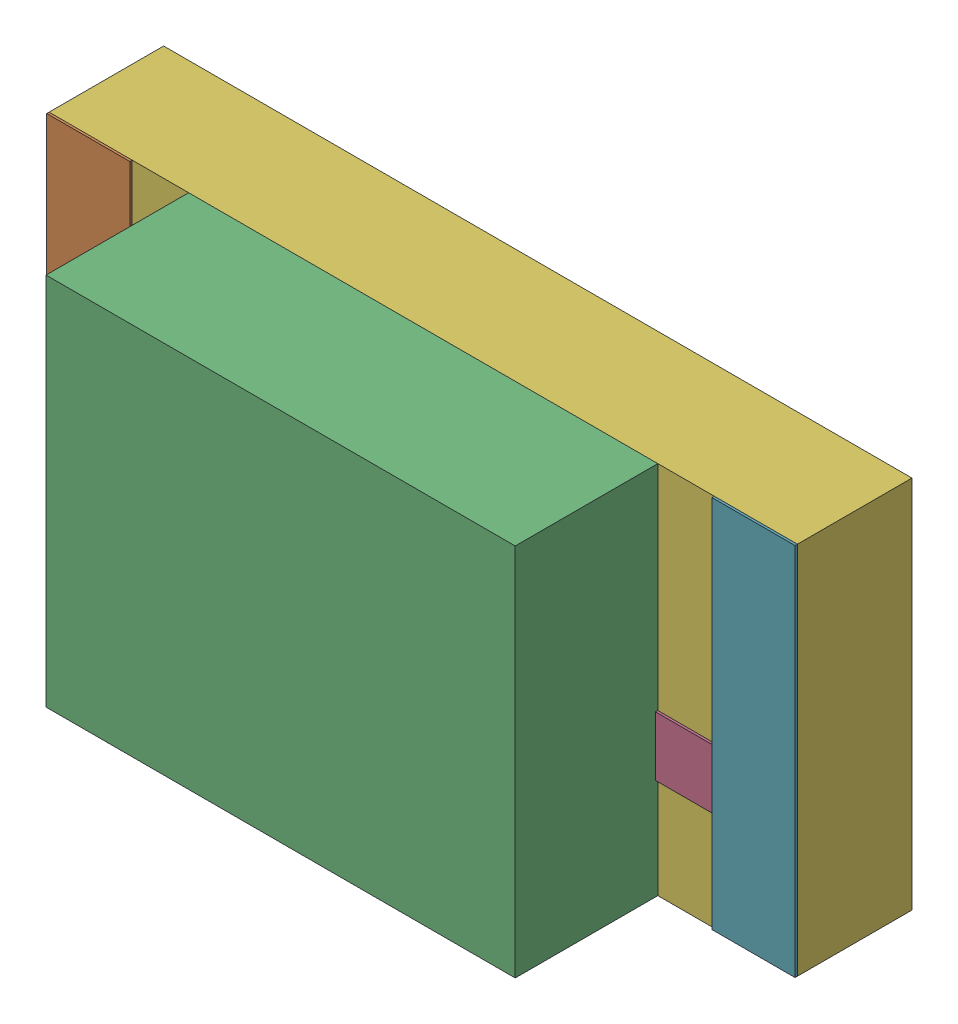
SolidWorks assembly SW3dPS-LED1206Y, configuration Défaut. Lengths in mm.
Overall size (3.2 1.6 1.52).
14 component instances, 6 part files, 0 mates.
Components (placement in the parent):
- SW3dPS-LED1206Y_Board-1: SW3dPS-LED1206Y_Board [Défaut] at (0 0 -0.4039) size (0.03 0.03 0.42)
- SW3dPS-LED1206Y_Open_CASCADE_STEP_translator_6.2_294.2-1: SW3dPS-LED1206Y_Open_CASCADE_STEP_translator_6.2_294.2 [Défaut] at origin size (3.2 1.6 1.1)
  - SW3dPS-LED1206Y_352697808-1: SW3dPS-LED1206Y_352697808 [Défaut] at (0.1016 0.0127 0.5027) size (0.36 1.6 0.01)
    - SW3dPS-LED1206Y_Extruded2-1: SW3dPS-LED1206Y_Extruded2 [Défaut] at origin size (0.36 1.6 0.01)
  - SW3dPS-LED1206Y_352697680-1: SW3dPS-LED1206Y_352697680 [Défaut] at (1.524 0.0127 0.5027) size (2.01 1.6 0.61)
    - SW3dPS-LED1206Y_Extruded4-1: SW3dPS-LED1206Y_Extruded4 [Défaut] at origin size (2.01 1.6 0.61)
  - SW3dPS-LED1206Y_352698192-1: SW3dPS-LED1206Y_352698192 [Défaut] at (2.1971 0.0254 0.5027) size (1.14 0.76 0.01)
    - SW3dPS-LED1206Y_Extruded3-1: SW3dPS-LED1206Y_Extruded3 [Défaut] at origin size (1.14 0.76 0.01)
  - SW3dPS-LED1206Y_352699472-1: SW3dPS-LED1206Y_352699472 [Défaut] at (0.6096 0.0254 0.5027) size (0.65 0.76 0.01)
    - SW3dPS-LED1206Y_Extruded-1: SW3dPS-LED1206Y_Extruded [Défaut] at origin size (0.65 0.76 0.01)
  - SW3dPS-LED1206Y_352697936-1: SW3dPS-LED1206Y_352697936 [Défaut] at (1.524 0.0127 0.0127) size (3.2 1.6 0.49)
    - SW3dPS-LED1206Y_Extruded1-1: SW3dPS-LED1206Y_Extruded1 [Défaut] at origin size (3.2 1.6 0.49)
  - SW3dPS-LED1206Y_352697808-2: SW3dPS-LED1206Y_352697808 [Défaut] at (2.9464 0.0127 0.5027) size (0.36 1.6 0.01)
    - SW3dPS-LED1206Y_Extruded2-1: SW3dPS-LED1206Y_Extruded2 [Défaut] at origin size (0.36 1.6 0.01)
